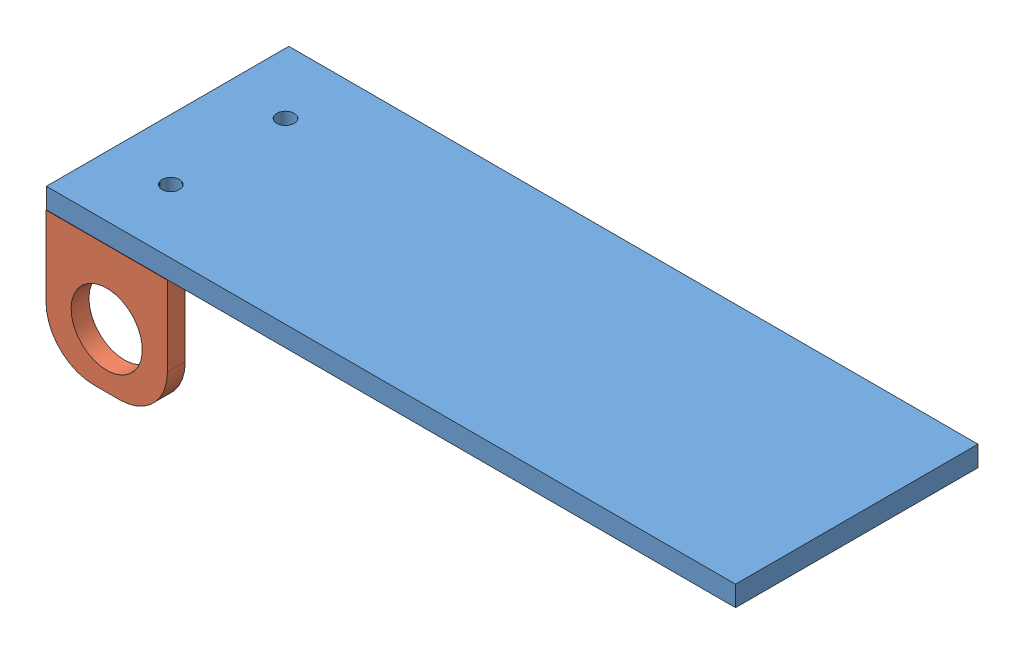
SolidWorks assembly project4_Assembly_stabilis, configuration Default. Lengths in mm.
Overall size (222.61 46.41 76.2).
12 component instances, 8 part files, 21 mates.
Components (placement in the parent):
- project4_main_body_stabilis-1: project4_main_body_stabilis [Default] at (-8.5443 123.4575 210.8349) size (216.26 6.4 76.08)
- project4_spring_wall_stabilis-1: project4_spring_wall_stabilis [Default] at (-37.6048 129.8575 148.6982) x (0 0 1) z (1 0 0) size (76.2 51.56 6.35) (hidden)
- project4_f_wheel_mount_stabilis-1: project4_f_wheel_mount_stabilis [Default] at (-31.2548 79.4192 148.3027) x (0 0 -1) z (1 0 0) size (76.2 40.01 38.1)
- project4_ball_bearing_stabilis-1: project4_ball_bearing_stabilis [6138K66] at (-12.2048 100.5975 152.3922) size (22.23 22.23 7.14) (hidden)
- project4_ball_bearing_stabilis-2: project4_ball_bearing_stabilis [6138K66] at (-12.2048 100.5975 221.4484) size (22.23 22.23 7.14) (hidden)
- project4_axle_stabilis-1: project4_axle_stabilis [Default] at (-12.2048 100.5975 133.0575) x (0.965021 -0.262172 0) z (0 0 1) size (9.53 9.53 107) (hidden)
- project4_wheel_stabilis-1: project4_wheel_stabilis [Default] at (-12.2048 100.5975 133.0575) size (50.8 50.8 12.7) (hidden)
- project4_wheel_stabilis-2: project4_wheel_stabilis [Default] at (-12.2048 100.5975 227.3575) size (50.8 50.8 12.7) (hidden)
- bolt_stabilis-1: bolt_stabilis [92095A183] at (-39.2548 116.0275 176.7982) x (0 0 1) z (-1 0 0) size (5.7 5.7 13.83) (hidden)
- bolt_stabilis-2: bolt_stabilis [92095A183] at (-39.2548 116.0275 196.6782) x (0 0 1) z (-1 0 0) size (5.7 5.7 13.83) (hidden)
- nut_stabilis-1: nut_stabilis [91854A108] at (-27.0548 116.0198 196.7656) x (0 0.594142 0.80436) z (-1 0 0) size (5.5 6.35 2.71) (hidden)
- nut_stabilis-2: nut_stabilis [91854A108] at (-27.0548 116.0804 176.8976) x (0 0.998979 0.045173) z (-1 0 0) size (5.5 6.35 2.71) (hidden)
Mates (geometry in assembly coordinates):
- Coincident3: coincident aligned: line of MainBody_mech2020_proj4-1 through (-31.2548 129.8575 148.8203) axis (0 0 1); line of SpringWall_mech2020_proj4-1 through (-31.2548 129.8575 148.6982) axis (0 0 1)
- Coincident4: coincident anti-aligned: plane of MainBody_mech2020_proj4-1 through (-31.2548 129.8575 224.8982) normal (-1 0 0); plane of SpringWall_mech2020_proj4-1 through (-31.2548 129.8575 148.6982) normal (1 0 0)
- Coincident5: coincident aligned: line of MainBody_mech2020_proj4-1 through (-31.2548 129.8575 224.8982) axis (0 -1 0); line of SpringWall_mech2020_proj4-1 through (-31.2548 129.8575 224.8982) axis (0 -1 0)
- Coincident6: coincident anti-aligned: plane of MainBody_mech2020_proj4-1 through (-8.5443 123.4575 210.8349) normal (0 -1 0); plane of FrontWheelHolder_mech2020_proj4-1 through (6.8452 123.4575 225.0203) normal (0 1 0)
- Coincident7: coincident aligned: line of MainBody_mech2020_proj4-1 through (185.0017 123.4575 148.8203) axis (-1 0 0); line of FrontWheelHolder_mech2020_proj4-1 through (6.8452 123.4575 148.8203) axis (-1 0 0)
- Coincident8: coincident aligned: line of MainBody_mech2020_proj4-1 through (-31.2548 123.4575 148.8203) axis (0 0 1); line of FrontWheelHolder_mech2020_proj4-1 through (-31.2548 123.4575 148.8203) axis (0 0 1)
- Concentric1: concentric aligned: cylinder of FrontWheelHolder_mech2020_proj4-1 through (-12.2048 100.5975 116.3083) axis (0 0 1) radius 11.176; cylinder of STAINLESS STEEL BALL BEARING-1 through (-12.2048 100.5975 155.9641) axis (0 0 1) radius 11.1125
- Coincident9: coincident aligned: plane of FrontWheelHolder_mech2020_proj4-1 through (6.8452 123.4575 148.8203) normal (0 0 -1); plane of STAINLESS STEEL BALL BEARING-1 through (-12.2048 111.3528 148.8203) normal (0 0 -1)
- Concentric2: concentric anti-aligned: cylinder of FrontWheelHolder_mech2020_proj4-1 through (-12.2048 100.5975 257.5323) axis (0 0 -1) radius 11.176; cylinder of STAINLESS STEEL BALL BEARING-2 through (-12.2048 100.5975 225.0203) axis (0 0 1) radius 11.1125
- Coincident10: coincident aligned: plane of FrontWheelHolder_mech2020_proj4-1 through (6.8452 123.4575 225.0203) normal (0 0 1); plane of STAINLESS STEEL BALL BEARING-2 through (-12.2048 111.3528 225.0203) normal (0 0 1)
- Concentric3: concentric anti-aligned: cylinder of STAINLESS STEEL BALL BEARING-1 through (-12.2048 100.5975 155.9641) axis (0 0 1) radius 4.7625; cylinder of real axel-1 through (-12.2048 100.5975 240.0575) axis (0 0 -1) radius 4.7625
- Concentric4: concentric aligned: cylinder of real axel-1 through (-12.2048 100.5975 240.0575) axis (0 0 -1) radius 4.7625; cylinder of Wheel-2 through (-12.2048 100.5975 240.0575) axis (0 0 -1) radius 4
- Coincident11: coincident aligned: plane of real axel-1 through (-12.2048 100.5975 240.0575) normal (0 0 1); plane of Wheel-2 through (-12.2048 100.5975 240.0575) normal (0 0 1)
- Concentric5: concentric aligned: cylinder of real axel-1 through (-12.2048 100.5975 240.0575) axis (0 0 -1) radius 4.7625; cylinder of Wheel-1 through (-12.2048 100.5975 145.7575) axis (0 0 -1) radius 4
- Coincident12: coincident aligned: plane of real axel-1 through (-12.2048 100.5975 133.0575) normal (0 0 -1); plane of Wheel-1 through (-12.2048 100.5975 133.0575) normal (0 0 -1)
- Coincident13: coincident anti-aligned: circle of SpringWall_mech2020_proj4-1; circle of bolt_stabilis-2
- Coincident15: coincident anti-aligned: circle of SpringWall_mech2020_proj4-1; circle of bolt_stabilis-3
- Coincident16: coincident anti-aligned: circle of SpringWall_mech2020_proj4-1; circle of 92095A183_BUTTON HEAD HEX DRIVE SCREW-1
- Coincident17: coincident anti-aligned: circle of SpringWall_mech2020_proj4-1; circle of 92095A183_BUTTON HEAD HEX DRIVE SCREW-2
- Coincident20: coincident anti-aligned: plane of FrontWheelHolder_mech2020_proj4-1 through (-28.2548 113.7768 213.5621) normal (1 0 0); plane of 91854A108_ALUMINUM HEX NUT-1 through (-28.2548 115.663 193.6102) normal (-1 0 0)
- Coincident22: coincident anti-aligned: plane of FrontWheelHolder_mech2020_proj4-1 through (-28.2548 113.7768 213.5621) normal (1 0 0); plane of 91854A108_ALUMINUM HEX NUT-2 through (-28.2548 113.4049 175.1873) normal (-1 0 0)
